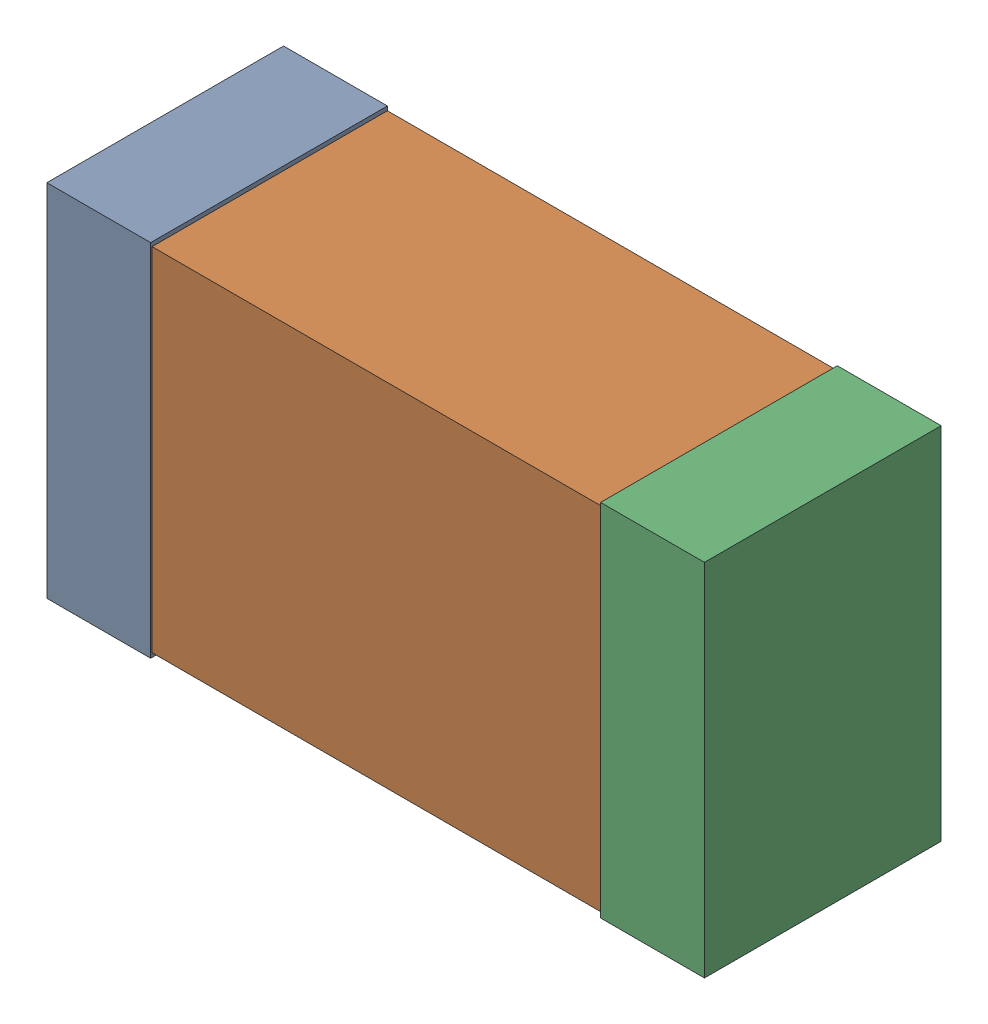
SolidWorks assembly C13_Motor_2Kanaloa_v2.0.0_Motor, configuration Default. Lengths in mm.
Overall size (2.38 1.3 0.85).
6 component instances, 2 part files, 0 mates.
Components (placement in the parent):
- 352877648-1: 352877648 [Default] at (144.986 59.69 0) size (0.38 1.3 0.85)
  - Extruded_14-1: Extruded_14 [Default] at origin size (0.38 1.3 0.85)
- 352877392-1: 352877392 [Default] at (145.986 59.69 0) size (2.2 1.27 0.85)
  - Extruded_15-1: Extruded_15 [Default] at origin size (2.2 1.27 0.85)
- 352877648-2: 352877648 [Default] at (146.986 59.69 0) size (0.38 1.3 0.85)
  - Extruded_14-1: Extruded_14 [Default] at origin size (0.38 1.3 0.85)
